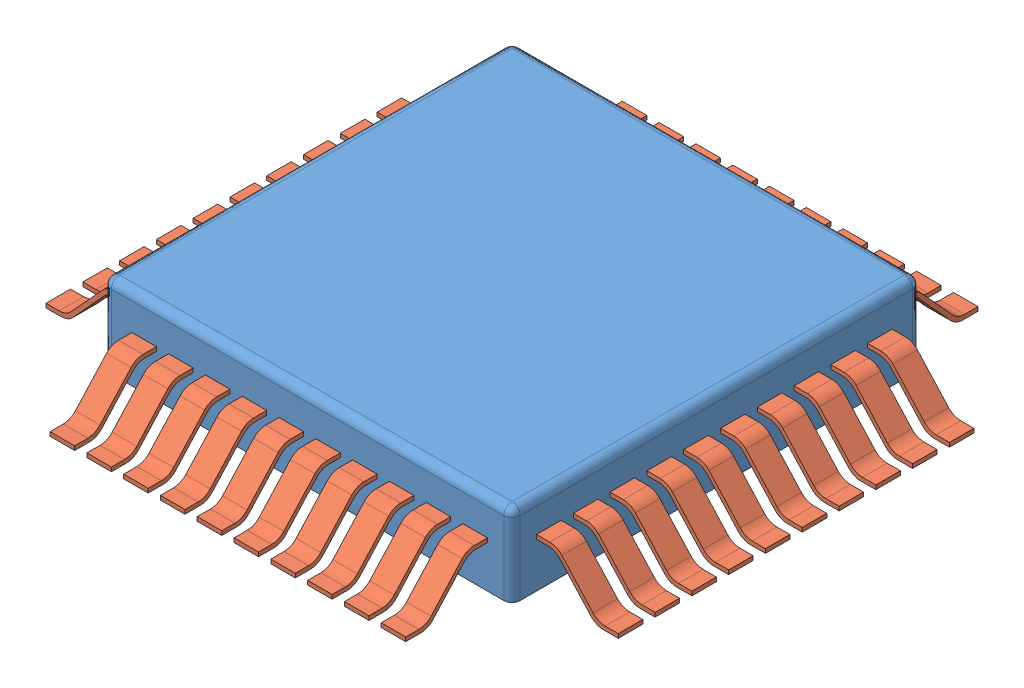
SolidWorks assembly 3652, configuration Default. Lengths in mm.
Overall size (7 1.04 7).
41 component instances, 2 part files, 6 mates.
Components (placement in the parent):
- 333-1: 333 [Default] at (-0.2652 1.6373 6.4642) size (5 1 5)
- 00.2-1: 00.2 [Default] at (4.7348 2.2373 1.9642) size (1 0.6 0.3)
- 00.2-2: 00.2 [Default] at (4.7348 2.2373 2.4142) size (1 0.6 0.3)
- 00.2-3: 00.2 [Default] at (4.7348 2.2373 2.8642) size (1 0.6 0.3)
- 00.2-4: 00.2 [Default] at (4.7348 2.2373 3.3142) size (1 0.6 0.3)
- 00.2-5: 00.2 [Default] at (4.7348 2.2373 3.7642) size (1 0.6 0.3)
- 00.2-6: 00.2 [Default] at (4.7348 2.2373 4.2142) size (1 0.6 0.3)
- 00.2-7: 00.2 [Default] at (4.7348 2.2373 4.6642) size (1 0.6 0.3)
- 00.2-8: 00.2 [Default] at (4.7348 2.2373 5.1142) size (1 0.6 0.3)
- 00.2-9: 00.2 [Default] at (4.7348 2.2373 5.5642) size (1 0.6 0.3)
- 00.2-10: 00.2 [Default] at (4.7348 2.2373 6.0142) size (1 0.6 0.3)
- 00.2-11: 00.2 [Default] at (-0.2652 2.2373 2.4142) x (-1 0 0) z (0 0 -1) size (1 0.6 0.3)
- 00.2-12: 00.2 [Default] at (-0.2652 2.2373 2.8642) x (-1 0 0) z (0 0 -1) size (1 0.6 0.3)
- 00.2-13: 00.2 [Default] at (-0.2652 2.2373 3.3142) x (-1 0 0) z (0 0 -1) size (1 0.6 0.3)
- 00.2-14: 00.2 [Default] at (-0.2652 2.2373 3.7642) x (-1 0 0) z (0 0 -1) size (1 0.6 0.3)
- 00.2-15: 00.2 [Default] at (-0.2652 2.2373 4.2142) x (-1 0 0) z (0 0 -1) size (1 0.6 0.3)
- 00.2-16: 00.2 [Default] at (-0.2652 2.2373 4.6642) x (-1 0 0) z (0 0 -1) size (1 0.6 0.3)
- 00.2-17: 00.2 [Default] at (-0.2652 2.2373 5.1142) x (-1 0 0) z (0 0 -1) size (1 0.6 0.3)
- 00.2-18: 00.2 [Default] at (-0.2652 2.2373 5.5642) x (-1 0 0) z (0 0 -1) size (1 0.6 0.3)
- 00.2-19: 00.2 [Default] at (-0.2652 2.2373 6.0142) x (-1 0 0) z (0 0 -1) size (1 0.6 0.3)
- 00.2-20: 00.2 [Default] at (0.2348 2.2019 6.4642) x (0 0 1) z (-1 0 0) size (1 0.6 0.3)
- 00.2-21: 00.2 [Default] at (-0.2652 2.2373 1.9642) x (-1 0 0) z (0 0 -1) size (1 0.6 0.3)
- 00.2-22: 00.2 [Default] at (0.6848 2.2019 6.4642) x (0 0 1) z (-1 0 0) size (1 0.6 0.3)
- 00.2-23: 00.2 [Default] at (1.1348 2.2019 6.4642) x (0 0 1) z (-1 0 0) size (1 0.6 0.3)
- 00.2-24: 00.2 [Default] at (1.5848 2.2019 6.4642) x (0 0 1) z (-1 0 0) size (1 0.6 0.3)
- 00.2-25: 00.2 [Default] at (2.0348 2.2019 6.4642) x (0 0 1) z (-1 0 0) size (1 0.6 0.3)
- 00.2-26: 00.2 [Default] at (2.4848 2.2019 6.4642) x (0 0 1) z (-1 0 0) size (1 0.6 0.3)
- 00.2-27: 00.2 [Default] at (2.9348 2.2019 6.4642) x (0 0 1) z (-1 0 0) size (1 0.6 0.3)
- 00.2-28: 00.2 [Default] at (3.3848 2.2019 6.4642) x (0 0 1) z (-1 0 0) size (1 0.6 0.3)
- 00.2-29: 00.2 [Default] at (3.8348 2.2019 6.4642) x (0 0 1) z (-1 0 0) size (1 0.6 0.3)
- 00.2-30: 00.2 [Default] at (4.2848 2.2019 6.4642) x (0 0 1) z (-1 0 0) size (1 0.6 0.3)
- 00.2-31: 00.2 [Default] at (0.6848 2.2019 1.4642) x (0 0 -1) z (1 0 0) size (1 0.6 0.3)
- 00.2-32: 00.2 [Default] at (1.1348 2.2019 1.4642) x (0 0 -1) z (1 0 0) size (1 0.6 0.3)
- 00.2-33: 00.2 [Default] at (1.5848 2.2019 1.4642) x (0 0 -1) z (1 0 0) size (1 0.6 0.3)
- 00.2-34: 00.2 [Default] at (2.0348 2.2019 1.4642) x (0 0 -1) z (1 0 0) size (1 0.6 0.3)
- 00.2-35: 00.2 [Default] at (2.4848 2.2019 1.4642) x (0 0 -1) z (1 0 0) size (1 0.6 0.3)
- 00.2-36: 00.2 [Default] at (2.9348 2.2019 1.4642) x (0 0 -1) z (1 0 0) size (1 0.6 0.3)
- 00.2-37: 00.2 [Default] at (3.3848 2.2019 1.4642) x (0 0 -1) z (1 0 0) size (1 0.6 0.3)
- 00.2-38: 00.2 [Default] at (3.8348 2.2019 1.4642) x (0 0 -1) z (1 0 0) size (1 0.6 0.3)
- 00.2-39: 00.2 [Default] at (4.2848 2.2019 1.4642) x (0 0 -1) z (1 0 0) size (1 0.6 0.3)
- 00.2-40: 00.2 [Default] at (0.2348 2.2019 1.4642) x (0 0 -1) z (1 0 0) size (1 0.6 0.3)
Mates (geometry in assembly coordinates):
- Coincident1: coincident: plane of 333-1 through (4.7348 2.6373 6.4642) normal (1 0 0); plane of 00.2-1 through (4.7348 2.1873 2.1142) normal (-1 0 0)
- Distance2: distance = 0.25 mm: line of 00.2-1 through (4.7348 2.2373 1.8142) axis (0 -1 0); line of 333-1 through (4.7348 1.6373 1.5642) axis (0 1 0)
- Distance3: distance = 0.3 mm: line of 00.2-1 through (4.7348 2.2373 2.1142) axis (0 0 -1); line of 333-1 through (4.7348 2.5373 1.5642) axis (0 0 1)
- Coincident10: coincident: plane of 333-1 through (-0.2652 2.6373 6.4642) normal (0 0 1); plane of 00.2-20 through (0.0848 2.1519 6.4642) normal (0 0 -1)
- Distance11: distance = 0.25 mm: line of 00.2-20 through (0.0848 2.2019 6.4642) axis (0 -1 0); line of 333-1 through (-0.1652 2.5373 6.4642) axis (0 -1 0)
- Distance12: distance = 0.25 mm: line of 00.2-20 through (0.0848 2.2019 6.4642) axis (1 0 0); cylinder of 333-1 through (-0.2652 2.5373 6.3642) axis (1 0 0) radius 0.1
